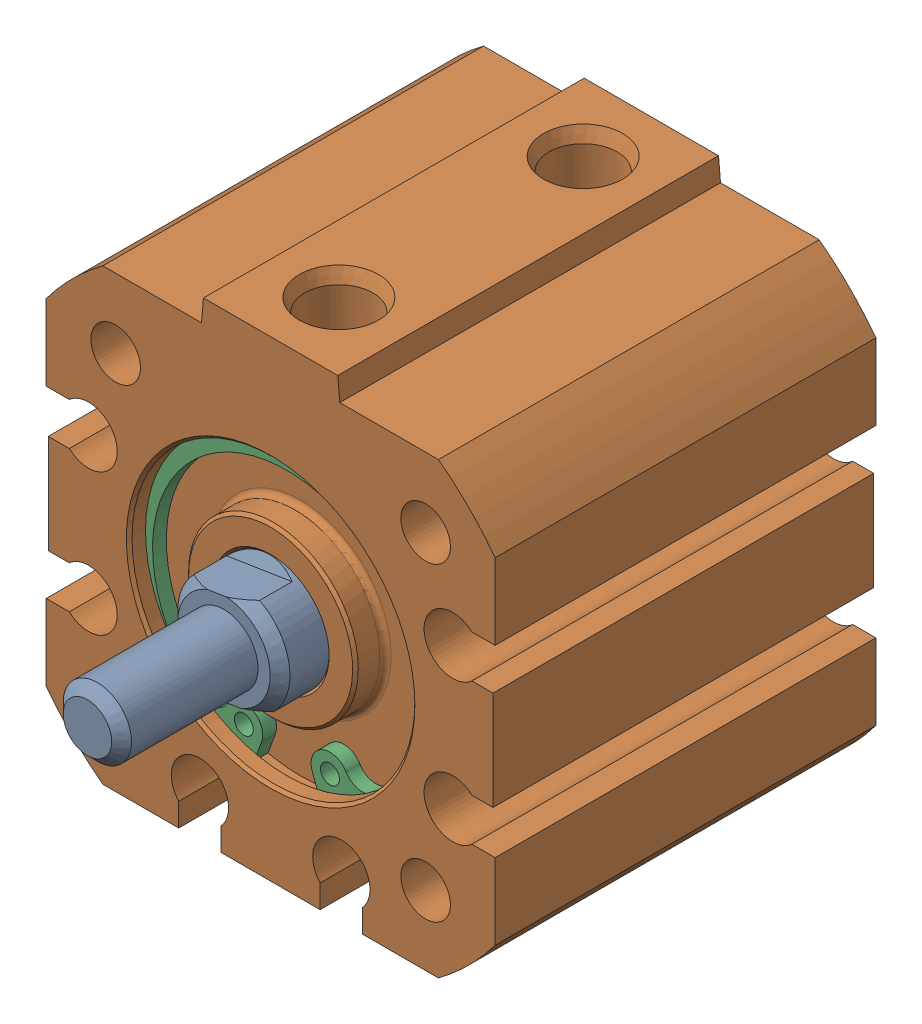
SolidWorks assembly 217-2778-001 Rev2_NCQ8A075-050M, configuration Default. Lengths in mm.
Overall size (31.75 33.34 39.88).
3 component instances, 3 part files, 0 mates.
Components (placement in the parent):
- 217-2778-003_075M-1: 217-2778-003_075M [Default] at (0 0 -8.85) x (0.156073 -0.987746 0) z (0 0 1) size (18.95 18.95 35.27)
- 217-2778-002_075A-1: 217-2778-002_075A [Default] at origin size (31.75 33.34 26.92)
- 217-2778-004_075-1: 217-2778-004_075 [Default] at (0 0 10.362) size (21 20.74 0.97)
